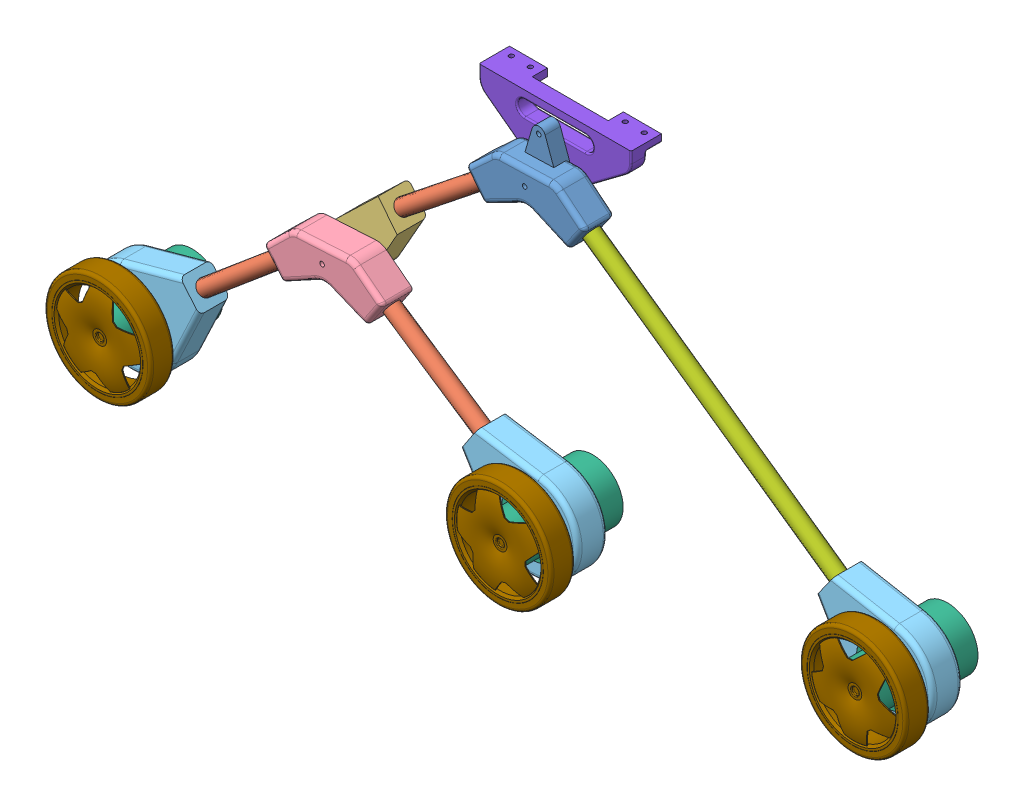
SolidWorks assembly BrazoCompleto, configuration Predeterminado. Lengths in mm.
Overall size (576.36 270.79 82.53).
17 component instances, 9 part files, 37 mates.
Components (placement in the parent):
- PiezaUnionBrazos-1: PiezaUnionBrazos [Predeterminado] at (-11.1471 0.4181 -10) x (0.999555 0.029816 0) z (0 0 1) size (77.79 51.56 20)
- BrazoUnionBogieBase-1: BrazoUnionBogieBase [Predeterminado] at (-109.5583 -52.4986 0) x (0.781755 0.623586 0) z (0 0 1) size (93 10 10)
- BrazoUnionBogieBase-2: BrazoUnionBogieBase [Predeterminado] at (-98.8984 -82.7068 18.5) x (0.831782 -0.555102 0) z (-0.555102 -0.831782 0.000131) size (93 10 10)
- PiezaUnionBogieBase-1: PiezaUnionBogieBase [Predeterminado] at (-10.4421 0.9805 -10) x (0.999555 0.029816 0) z (0 0 1) size (45 51.53 27)
- PiezaUnionBogie-1: PiezaUnionBogie [Predeterminado] at (-12.4051 3.8391 10) x (0.998487 0.054988 0) z (0 0 1) size (77.79 32.56 20)
- BrazoUnionBogieBase-3: BrazoUnionBogieBase [Predeterminado] at (-221.1306 -145.3228 18.5) x (0.765797 0.643083 0) z (0.54222 -0.645687 0.537667) size (93 10 10)
- SoporteRuedas-1: SoporteRuedas [Predeterminado] at (-27.0304 -8.4425 8.5) x (0.998487 0.054988 0) z (0 0 1) size (76 68 20)
- SoporteRuedas-2: SoporteRuedas [Predeterminado] at (-207.2958 13.6785 8.5) x (-0.332365 0.943151 0) z (0 0 1) size (76 68 20)
- RuedayMotor-1: RuedayMotor [Predeterminado] at (-251.7625 -171.0461 -11.5) x (0.999886 0.015114 0) z (0 0 1) size (40 40 60)
- RuedayMotor-2: RuedayMotor [Predeterminado] at (11.7286 -156.5353 -11.5) x (-0.759364 0.650667 0) z (0 0 1) size (40 40 60)
- BrazoUnionRocker-1: BrazoUnionRocker [Predeterminado] at (14.2125 7.0182 0) x (0.817534 -0.57588 0) z (-0.572053 -0.8121 -0.115103) size (220 10.1 10.1)
- SoporteRuedas-3: SoporteRuedas [Predeterminado] at (12.1046 32.9669 -10) x (-0.308499 0.951225 0) z (0 0 1) size (76 68 20)
- RuedayMotor-3: RuedayMotor [Predeterminado] at (226.7714 -142.7106 -30) x (1 -0.000005 0) z (0 0 1) size (40 40 60)
- PiezaBrazoBase-1: PiezaBrazoBase [Predeterminado] at (-11.5944 0.4114 -15) size (100 47.5 27)
- Ruedita-1: Ruedita [Default] at (-251.7625 -171.0461 48) x (0.762907 -0.646508 0) z (0 0 1) size (70 70 17.53)
- Ruedita-2: Ruedita [Default] at (11.7286 -156.5353 48) x (-0.049675 -0.998765 0) z (0 0 1) size (70 70 17.53)
- Ruedita-3: Ruedita [Default] at (226.7714 -142.7106 29.5) x (-0.834322 0.551278 0) z (0 0 1) size (70 70 17.53)
Mates (geometry in assembly coordinates):
- Concéntrica1: concentric aligned: cylinder of PiezaUnionBrazos-1 through (-36.8551 5.4949 0) axis (-0.781755 -0.623586 0) radius 5.05; cylinder of BrazoUnionBogieBase-1 through (-36.8551 5.4949 0) axis (-0.781755 -0.623586 0) radius 5
- Coincidente1: coincident anti-aligned: plane of PiezaUnionBrazos-1 through (-36.8551 5.4949 0) normal (-0.781755 -0.623586 0); plane of BrazoUnionBogieBase-1 through (-36.8551 5.4949 0) normal (0.781755 0.623586 0)
- Coincidente3: coincident anti-aligned: plane of PiezaUnionBogieBase-1 through (-124.8793 -75.4973 17) normal (0 0 1); plane of PiezaUnionBogie-1 through (-124.8793 -75.4973 17) normal (0 0 -1)
- Concéntrica4: concentric anti-aligned: cylinder of BrazoUnionBogieBase-2 through (-21.5427 -134.3312 18.5) axis (-0.831782 0.555102 0) radius 5; cylinder of PiezaUnionBogie-1 through (-98.8984 -82.7068 18.5) axis (0.831782 -0.555102 0) radius 5.05
- Coincidente4: coincident anti-aligned: plane of BrazoUnionBogieBase-2 through (-98.8984 -82.7068 18.5) normal (-0.831782 0.555102 0); plane of PiezaUnionBogie-1 through (-98.8984 -82.7068 18.5) normal (0.831782 -0.555102 0)
- Concéntrica5: concentric aligned: cylinder of PiezaUnionBogie-1 through (-149.9115 -85.5161 18.5) axis (-0.765797 -0.643083 0) radius 5.05; cylinder of BrazoUnionBogieBase-3 through (-149.9115 -85.5161 18.5) axis (-0.765797 -0.643083 0) radius 5
- Coincidente5: coincident anti-aligned: plane of PiezaUnionBogie-1 through (-149.9115 -85.5161 18.5) normal (-0.765797 -0.643083 0); plane of BrazoUnionBogieBase-3 through (-149.9115 -85.5161 18.5) normal (0.765797 0.643083 0)
- Coincidente6: coincident anti-aligned: plane of BrazoUnionBogieBase-1 through (-109.5583 -52.4986 0) normal (-0.781755 -0.623586 0); plane of PiezaUnionBogieBase-1 through (-109.5583 -52.4986 0) normal (0.781755 0.623586 0)
- Concéntrica6: concentric anti-aligned: cylinder of BrazoUnionBogieBase-1 through (-36.8551 5.4949 0) axis (-0.781755 -0.623586 0) radius 5; cylinder of PiezaUnionBogieBase-1 through (-109.5583 -52.4986 0) axis (0.781755 0.623586 0) radius 5.05
- Concéntrica7: concentric aligned: cylinder of PiezaUnionBogieBase-1 through (-124.8793 -75.4973 17) axis (0 0 -1) radius 6; cylinder of PiezaUnionBogie-1 through (-124.8793 -75.4973 17) axis (0 0 -1) radius 6
- Concéntrica8: concentric anti-aligned: cylinder of BrazoUnionBogieBase-3 through (-149.9115 -85.5161 18.5) axis (-0.765797 -0.643083 0) radius 5; cylinder of SoporteRuedas-1 through (-221.1306 -145.3228 18.5) axis (0.765797 0.643083 0) radius 5.05
- Coincidente7: coincident anti-aligned: plane of BrazoUnionBogieBase-3 through (-221.1306 -145.3228 18.5) normal (-0.765797 -0.643083 0); plane of SoporteRuedas-1 through (-221.1306 -145.3228 18.5) normal (0.765797 0.643083 0)
- Concéntrica10: concentric aligned: cylinder of BrazoUnionBogieBase-2 through (-21.5427 -134.3312 18.5) axis (-0.831782 0.555102 0) radius 5; cylinder of SoporteRuedas-2 through (-21.5427 -134.3312 18.5) axis (-0.831782 0.555102 0) radius 5.05
- Coincidente8: coincident anti-aligned: plane of BrazoUnionBogieBase-2 through (-21.5427 -134.3312 18.5) normal (0.831782 -0.555102 0); plane of SoporteRuedas-2 through (-21.5427 -134.3312 18.5) normal (-0.831782 0.555102 0)
- Concéntrica11: concentric aligned: cylinder of SoporteRuedas-1 through (-251.7625 -171.0461 28.5) axis (0 0 -1) radius 20; cylinder of RuedayMotor-1 through (-251.7625 -171.0461 28.5) axis (0 0 -1) radius 20
- Coincidente9: coincident aligned: plane of SoporteRuedas-1 through (-251.7625 -171.0461 28.5) normal (0 0 1); plane of RuedayMotor-1 through (-251.7625 -171.0461 28.5) normal (0 0 1)
- Concéntrica12: concentric aligned: cylinder of SoporteRuedas-2 through (11.7286 -156.5353 28.5) axis (0 0 -1) radius 20; cylinder of RuedayMotor-2 through (11.7286 -156.5353 28.5) axis (0 0 -1) radius 20
- Coincidente11: coincident aligned: plane of SoporteRuedas-2 through (11.7286 -156.5353 28.5) normal (0 0 1); plane of RuedayMotor-2 through (11.7286 -156.5353 28.5) normal (0 0 1)
- Concéntrica13: concentric anti-aligned: cylinder of PiezaUnionBrazos-1 through (14.2125 7.0182 0) axis (0.817534 -0.57588 0) radius 5.05; cylinder of BrazoUnionRocker-1 through (194.07 -119.6754 0) axis (-0.817534 0.57588 0) radius 5.05
- Coincidente12: coincident anti-aligned: plane of PiezaUnionBrazos-1 through (14.2125 7.0182 0) normal (0.817534 -0.57588 0); plane of BrazoUnionRocker-1 through (14.2125 7.0182 0) normal (-0.817534 0.57588 0)
- Concéntrica14: concentric aligned: cylinder of BrazoUnionRocker-1 through (194.07 -119.6754 0) axis (-0.817534 0.57588 0) radius 5.05; cylinder of SoporteRuedas-3 through (194.07 -119.6754 0) axis (-0.817534 0.57588 0) radius 5.05
- Coincidente13: coincident anti-aligned: plane of BrazoUnionRocker-1 through (194.07 -119.6754 0) normal (0.817534 -0.57588 0); plane of SoporteRuedas-3 through (194.07 -119.6754 0) normal (-0.817534 0.57588 0)
- Concéntrica15: concentric aligned: cylinder of SoporteRuedas-3 through (226.7714 -142.7106 10) axis (0 0 -1) radius 20; cylinder of RuedayMotor-3 through (226.7714 -142.7106 10) axis (0 0 -1) radius 20
- Coincidente14: coincident aligned: plane of SoporteRuedas-3 through (226.7714 -142.7106 10) normal (0 0 1); plane of RuedayMotor-3 through (226.7714 -142.7106 10) normal (0 0 1)
- Concéntrica16: concentric aligned: cylinder of PiezaUnionBrazos-1 through (-11.5944 15.4114 -3) axis (0 0 -1) radius 6; cylinder of PiezaBrazoBase-1 through (-11.5944 15.4114 -3) axis (0 0 -1) radius 6
- Coincidente16: coincident anti-aligned: plane of PiezaUnionBrazos-1 through (-11.5944 15.4114 -3) normal (0 0 -1); plane of PiezaBrazoBase-1 through (-11.5944 15.4114 -3) normal (0 0 1)
- Paralelo1: parallel aligned: plane of PiezaBrazoBase-1 through (-61.5944 50.4114 -10) normal (0 1 0)
- Concéntrica18: concentric aligned: cylinder of RuedayMotor-1 through (-251.7625 -171.0461 37.5) axis (0 0 1) radius 3.25; cylinder of Ruedita-1 through (-251.7625 -171.0461 48) axis (0 0 1) radius 3.25
- Coincidente21: coincident anti-aligned: plane of RuedayMotor-1 through (-251.7625 -171.0461 37.5) normal (0 0 1); plane of Ruedita-1 through (-250.1462 -169.1389 37.5) normal (0 0 -1)
- Concéntrica21: concentric aligned: cylinder of RuedayMotor-3 through (226.7714 -142.7106 19) axis (0 0 1) radius 3.25; cylinder of Ruedita-3 through (226.7714 -142.7106 29.5) axis (0 0 1) radius 3.25
- Concéntrica22: concentric aligned: cylinder of RuedayMotor-3 through (226.7714 -142.7106 19) axis (0 0 1) radius 3.25; cylinder of Ruedita-3 through (226.7714 -142.7106 29.5) axis (0 0 1) radius 3.25
- Coincidente22: coincident anti-aligned: plane of RuedayMotor-3 through (226.7714 -142.7106 19) normal (0 0 1); plane of Ruedita-3 through (225.3932 -144.7964 19) normal (0 0 -1)
- Paralelo7: parallel aligned: plane of PiezaUnionBogie-1 through (-108.6751 -74.0724 10) normal (0 0 -1); plane of SoporteRuedas-2 through (11.7286 -156.5353 8.5) normal (0 0 -1)
- Paralelo8: parallel aligned: plane of PiezaUnionBogie-1 through (-108.6751 -74.0724 10) normal (0 0 -1); plane of SoporteRuedas-1 through (-251.7625 -171.0461 8.5) normal (0 0 -1)
- Concéntrica23: concentric aligned: cylinder of RuedayMotor-2 through (11.7286 -156.5353 37.5) axis (0 0 1) radius 3.25; cylinder of Ruedita-2 through (11.7286 -156.5353 48) axis (0 0 1) radius 3.25
- Coincidente26: coincident anti-aligned: plane of RuedayMotor-2 through (11.7286 -156.5353 37.5) normal (0 0 1); plane of Ruedita-2 through (14.2255 -156.6595 37.5) normal (0 0 -1)
- Paralelo9: parallel aligned: plane of PiezaUnionBogieBase-1 through (-124.8793 -75.4973 -10) normal (0 0 -1); plane of PiezaUnionBrazos-1 through (-27.8452 14.9266 -10) normal (0 0 -1)
